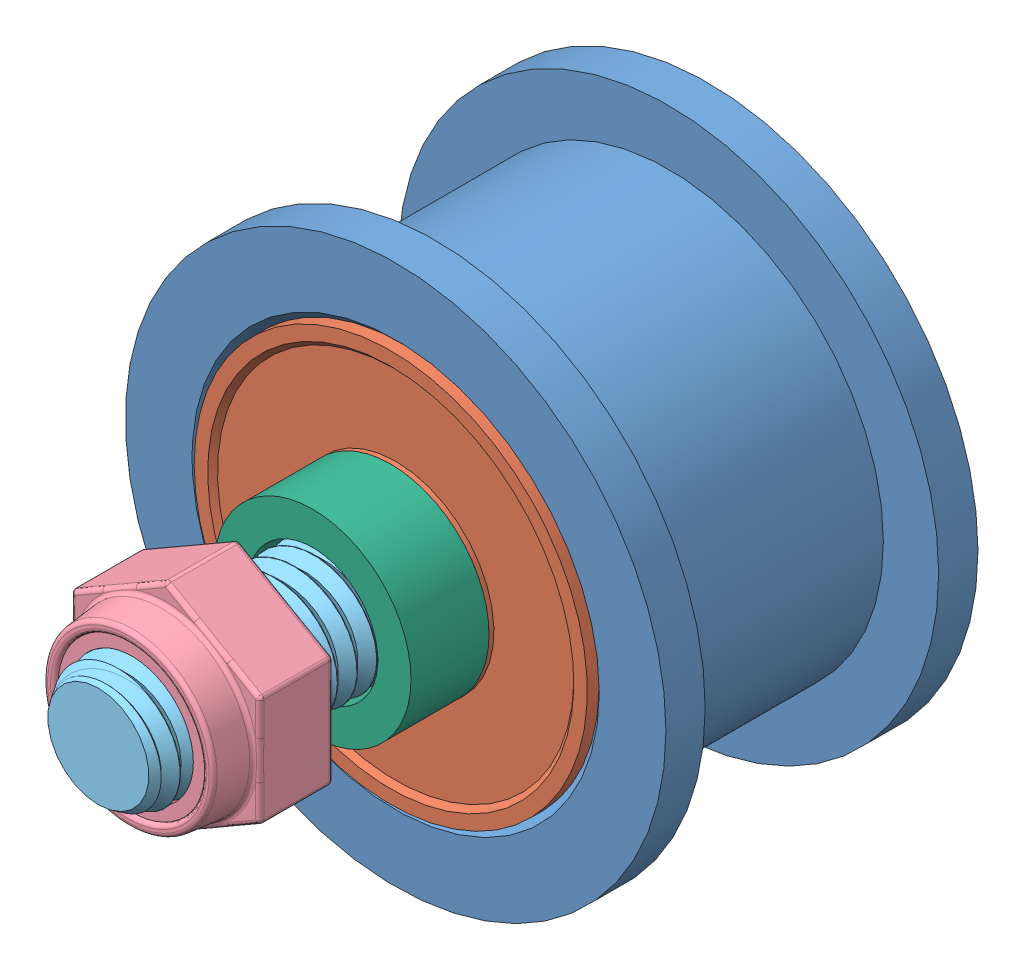
SolidWorks assembly Idler Wheel Assembly, configuration Default. Lengths in mm.
Overall size (22.57 22.57 27.2).
7 component instances, 6 part files, 12 mates.
Components (placement in the parent):
- V-Slot Idler Pulley-1: V-Slot Idler Pulley [Default] at (8.0419 11.7957 16.7627) size (22 22 12.7)
- Precision Ball Bearing-1: Precision Ball Bearing [Default] at (8.0419 11.7957 20.8127) x (0 0 1) z (-0.755442 -0.655215 0) size (5 16 16)
- Precision Ball Bearing-2: Precision Ball Bearing [Default] at (8.0419 11.7957 12.7127) x (0 0 1) z (-1 0 0) size (5 16 16)
- 5mm Precision Washer-1: 5mm Precision Washer [Default] at (8.0419 11.7957 17.3127) x (0 0 1) z (-1 0 0) size (1 10 10)
- Nylon Insert Hex Locknut 5mm-1: Nylon Insert Hex Locknut 5mm [Default] at (8.0419 11.7957 29.4877) size (7.68 8.82 4.5)
- 5mm x 25mm Low Profile Socket Head Screw-1: 5mm x 25mm Low Profile Socket Head Screw [Default] at (8.0419 11.7957 8.4627) x (0 0 1) z (-1 0 0) size (27.2 9.5 9.5)
- .125 Inch Aluminum Spacer-1: .125 Inch Aluminum Spacer [Default] at (8.0419 11.7957 23.3127) x (0 0 1) z (-1 0 0) size (3.17 8 8)
Mates (geometry in assembly coordinates):
- Concentric1: concentric anti-aligned: cylinder of V-Slot Idler Pulley-1 through (8.0419 11.7957 16.7627) axis (0 0 1) radius 7.9875; cylinder of Precision Ball Bearing-1 through (8.0419 11.7957 23.3127) axis (0 0 -1) radius 8
- Coincident1: coincident anti-aligned: plane of V-Slot Idler Pulley-1 through (8.0419 19.7832 18.3127) normal (0 0 1); plane of Precision Ball Bearing-1 through (8.0419 11.7957 18.3127) normal (0 0 -1)
- Coincident2: coincident anti-aligned: plane of Precision Ball Bearing-1 through (8.0419 11.7957 18.3127) normal (0 0 -1); plane of 5mm Precision Washer-1 through (8.0419 11.7957 18.3127) normal (0 0 1)
- Concentric2: concentric anti-aligned: cylinder of Precision Ball Bearing-1 through (8.0419 11.7957 18.3127) axis (0 0 1) radius 2.5; cylinder of 5mm Precision Washer-1 through (8.0419 11.7957 18.3127) axis (0 0 -1) radius 2.5
- Coincident3: coincident anti-aligned: plane of V-Slot Idler Pulley-1 through (8.0419 19.7832 15.2127) normal (0 0 -1); plane of Precision Ball Bearing-2 through (8.0419 11.7957 15.2127) normal (0 0 1)
- Concentric3: concentric anti-aligned: cylinder of V-Slot Idler Pulley-1 through (8.0419 11.7957 16.7627) axis (0 0 1) radius 7.9875; cylinder of Precision Ball Bearing-2 through (8.0419 11.7957 15.2127) axis (0 0 -1) radius 8
- Coincident4: coincident anti-aligned: plane of Precision Ball Bearing-2 through (8.0419 11.7957 10.2127) normal (0 0 -1); plane of 5mm x 25mm Low Profile Socket Head Screw-1 through (8.0419 14.2957 10.2127) normal (0 0 1)
- Concentric4: concentric anti-aligned: cylinder of Precision Ball Bearing-2 through (8.0419 11.7957 10.2127) axis (0 0 1) radius 2.5; cylinder of 5mm x 25mm Low Profile Socket Head Screw-1 through (8.0419 11.7957 8.4627) axis (0 0 -1) radius 4.75
- Coincident7: coincident anti-aligned: plane of Precision Ball Bearing-1 through (8.0419 11.7957 23.3127) normal (0 0 1); plane of .125 Inch Aluminum Spacer-1 through (8.0419 11.7957 23.3127) normal (0 0 -1)
- Concentric7: concentric anti-aligned: circle of Precision Ball Bearing-1; circle of .125 Inch Aluminum Spacer-1
- Distance2: distance = 3 mm: plane of .125 Inch Aluminum Spacer-1 through (8.0419 11.7957 26.4877) normal (0 0 1); plane of Nylon Insert Hex Locknut 5mm-1 through (8.0419 11.7957 29.4877) normal (0 0 -1)
- Concentric8: concentric aligned: circle of Nylon Insert Hex Locknut 5mm-1; circle of .125 Inch Aluminum Spacer-1
